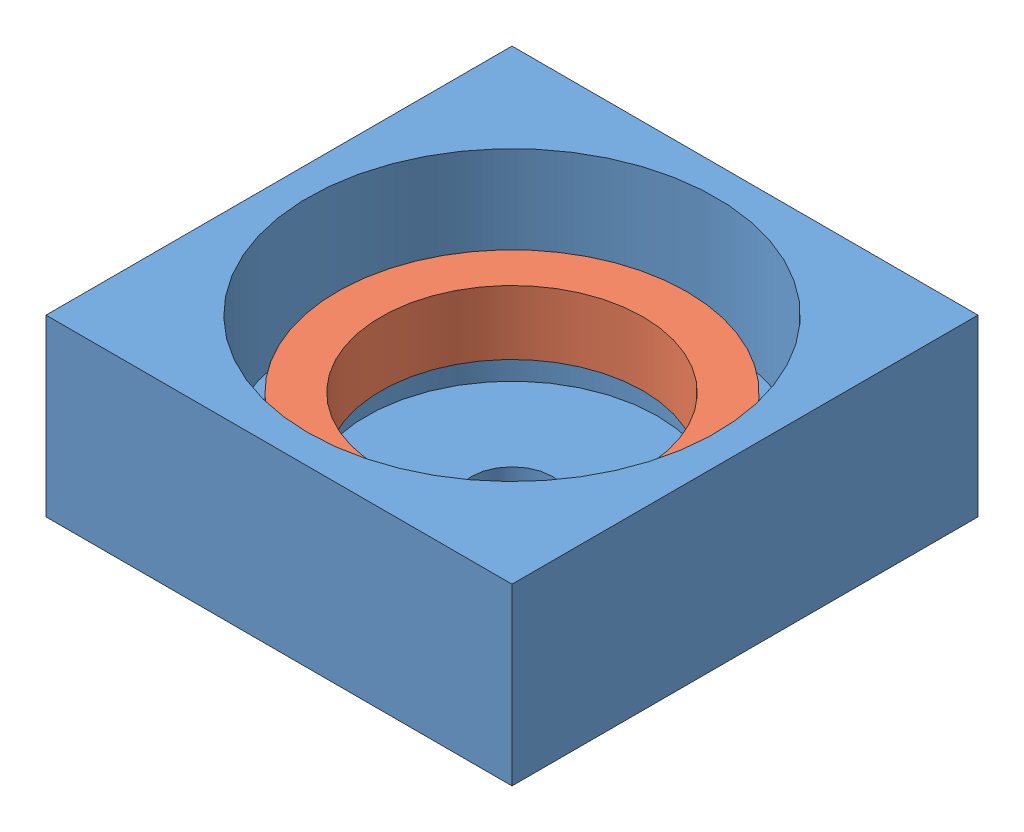
SolidWorks assembly 110303047-01, configuration 預設. Lengths in mm.
Overall size (160 60 160).
2 component instances, 2 part files, 1 mates.
Components (placement in the parent):
- 110303047-01-1: 110303047-01 [預設] at (-3.1161 -43.4484 160) size (160 60 160)
- 2-1: 2 [Default] at (-3.1161 -28.4484 160) size (120 22 120)
Mates (geometry in assembly coordinates):
- 輪廓中心1: profile center aligned: plane of 2-1 through (-3.1161 -28.4484 160) normal (0 -1 0); circle of 110303047-01-1
